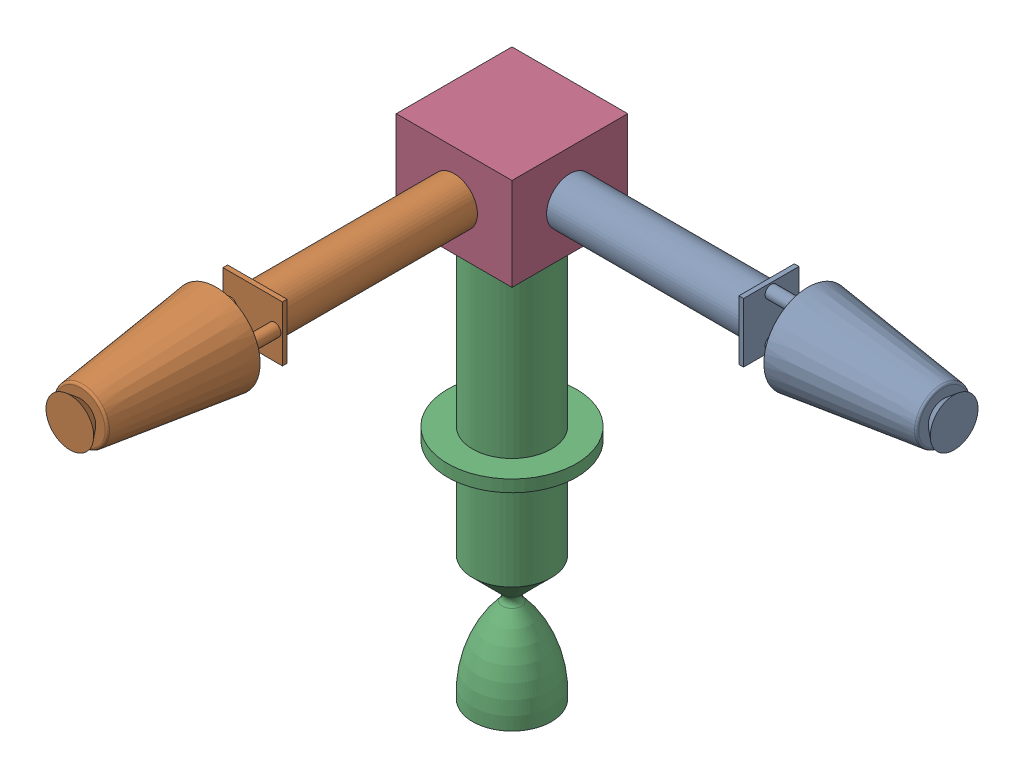
SolidWorks assembly Thruster Cluster, configuration Default. Lengths in mm.
Overall size (1980.23 2500 1980.23).
4 component instances, 3 part files, 6 mates.
Components (placement in the parent):
- MR-111C Thruster-1: MR-111C Thruster [Default] at (172.5085 87.7626 60.1114) x (0 1 0) z (0 0 1) size (38 169 38)
- MR-111C Thruster-2: MR-111C Thruster [Default] at (-18.4915 87.7626 251.1114) x (1 0 0) z (0 1 0) size (38 169 38)
- MR-106E Thruster-1: MR-106E Thruster [Default] at (-18.4915 -111.2374 60.1114) size (55.68 182 55.68)
- Thruster Mount-1: Thruster Mount [Default] at (-18.4915 67.7626 60.1114) size (50 40 50)
Mates (geometry in assembly coordinates):
- Concentric1: concentric aligned: circle of MR-111C Thruster-2; circle of Thruster Mount-1
- Coincident2: coincident anti-aligned: plane of MR-111C Thruster-2 through (-18.4915 87.7626 82.1114) normal (0 0 -1); plane of Thruster Mount-1 through (-18.4915 87.7626 82.1114) normal (0 0 1)
- Concentric3: concentric aligned: circle of MR-111C Thruster-1; circle of Thruster Mount-1
- Coincident4: coincident anti-aligned: plane of MR-111C Thruster-1 through (3.5085 87.7626 60.1114) normal (-1 0 0); plane of Thruster Mount-1 through (3.5085 87.7626 60.1114) normal (1 0 0)
- Concentric4: concentric aligned: circle of MR-106E Thruster-1; circle of Thruster Mount-1
- Coincident5: coincident anti-aligned: plane of MR-106E Thruster-1 through (-18.4915 70.7626 60.1114) normal (0 1 0); plane of Thruster Mount-1 through (-18.4915 70.7626 60.1114) normal (0 -1 0)
